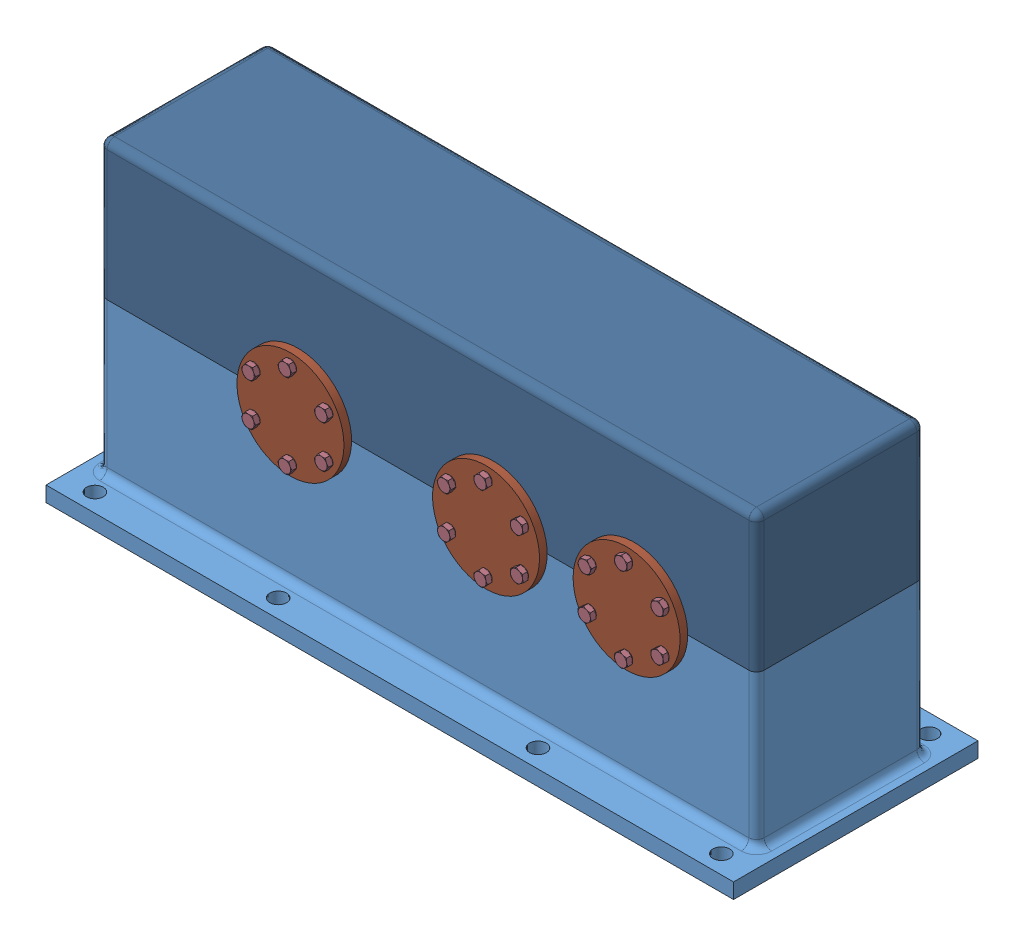
SolidWorks assembly gear box 1, configuration Default. Lengths in mm.
Overall size (450 208.96 200).
57 component instances, 13 part files, 131 mates.
Components (placement in the parent):
- housing-1: housing [Default] at (201.3675 171.3097 333.5833) size (450 110 160)
- 23T GEAR-1: 23T GEAR [Default] at (343.8267 281.2328 311.9535) x (0 0 -1) z (-0.038313 0.999266 0) size (25 49.84 49.95)
- 69T GEAR-1: 69T GEAR [Default] at (242.5131 286.1435 311.7084) x (0 0 -1) z (0.81521 -0.579166 0) size (25 141.95 141.99)
- 34T 2.5M GEAR-1: 34T 2.5M GEAR [Default] at (241.1812 276.7312 345.5837) x (0 0 -1) z (0.81521 -0.579166 0) size (25 89.74 90)
- 69T 2.5M GEAR-1: 69T 2.5M GEAR [Default] at (102.958 286.2942 359.4922) x (0 0 -1) z (-1 -0.00092 0) size (25 177.44 177.48)
- input shaft-1: input shaft [Default] at (336.3675 281.3097 388.5833) x (0 0 -1) z (-0.038313 0.999266 0) size (175 25 28.29)
- 1st stage shaft-1: 1st stage shaft [Default] at (244.3675 281.3097 388.5833) x (0 0 -1) z (0.81521 -0.579166 0) size (110 25 25)
- output shaft-1: output shaft [Default] at (116.3675 281.3097 388.5833) x (0 0 -1) z (-1 -0.00092 0) size (165 25 25)
- 6004 bearing-1: 6004 bearing [Default] at (123.168 277.2526 295.2471) x (0 0 -1) z (1 0 0) size (12 42 42)
- 6004 bearing-2: 6004 bearing [Default] at (251.168 277.2526 295.2471) x (0 0 -1) z (1 0 0) size (12 42 42)
- 6004 bearing-3: 6004 bearing [Default] at (343.2349 285.2524 387.2471) x (0 0 -1) z (0.489674 0.871906 0) size (12 42 42)
- 6004 bearing-4: 6004 bearing [Default] at (343.1288 277.1876 295.2471) x (0 0 -1) z (0.999954 -0.009577 0) size (12 42 42)
- 6004 bearing-5: 6004 bearing [Default] at (251.168 277.2526 387.2471) x (0 0 -1) z (1 0 0) size (12 42 42)
- 6004 bearing-6: 6004 bearing [Default] at (123.6132 278.115 387.2471) x (0 0 -1) z (0.99249 0.122329 0) size (12 42 42)
- top housing-1: top housing [Default] at (201.3675 281.3097 333.5833) size (430 90 110)
- bearing cover 01-1: bearing cover 01 [Default] at (116.3675 281.3097 393.5833) x (0 0 -1) z (0.866025 0.5 0) size (8 70 70)
- bearing cover 01-2: bearing cover 01 [Default] at (244.3675 281.3097 393.5833) x (0 0 -1) z (0.866025 0.5 0) size (8 70 70)
- bearing cover 01-3: bearing cover 01 [Default] at (336.3675 281.3097 393.5833) x (0 0 -1) z (-0.866025 0.5 0) size (8 70 70)
- bearing cover 01-5: bearing cover 01 [Default] at (244.3675 281.3097 273.5833) x (0 0 1) z (-0.866025 0.5 0) size (8 70 70)
- bearing cover 02-3: bearing cover 02 [Default] at (336.3675 281.3097 273.5833) x (0 0 1) z (-0.866025 -0.5 0) size (8 70 70)
- bearing cover 02-4: bearing cover 02 [Default] at (116.3675 281.3097 273.5833) x (0 0 1) z (-0.866025 0.5 0) size (8 70 70)
- hex bolt gradec_iso-2: hex bolt gradec_iso [ISO 4016 - M5 x 25 x 16-WN] at (336.3675 308.8097 397.4583) x (0 0 -1) z (0.550968 0.834527 0) size (28.88 9.24 8)
- hex bolt gradec_iso-3: hex bolt gradec_iso [ISO 4016 - M5 x 25 x 16-WN] at (360.1832 295.0597 397.4583) x (0 0 -1) z (-0.354568 0.93503 0) size (28.88 9.24 8)
- hex bolt gradec_iso-4: hex bolt gradec_iso [ISO 4016 - M5 x 25 x 16-WN] at (360.1832 267.5597 397.4583) x (0 0 -1) z (0.631634 -0.775267 0) size (28.88 9.24 8)
- hex bolt gradec_iso-5: hex bolt gradec_iso [ISO 4016 - M5 x 25 x 16-WN] at (336.3675 253.8097 397.4583) x (0 0 -1) z (0.631634 -0.775267 0) size (28.88 9.24 8)
- hex bolt gradec_iso-6: hex bolt gradec_iso [ISO 4016 - M5 x 25 x 16-WN] at (312.5518 267.5597 397.4583) x (0 0 -1) z (0.631634 -0.775267 0) size (28.88 9.24 8)
- hex bolt gradec_iso-7: hex bolt gradec_iso [ISO 4016 - M5 x 25 x 16-WN] at (312.5518 295.0597 397.4583) x (0 0 -1) z (0.762541 0.64694 0) size (28.88 9.24 8)
- hex bolt gradec_iso-8: hex bolt gradec_iso [ISO 4016 - M5 x 25 x 16-WN] at (268.1832 295.0597 397.4583) x (0 0 -1) z (0.631634 -0.775267 0) size (28.88 9.24 8)
- hex bolt gradec_iso-9: hex bolt gradec_iso [ISO 4016 - M5 x 25 x 16-WN] at (268.1832 267.5597 397.4583) x (0 0 -1) z (0.99571 0.092525 0) size (28.88 9.24 8)
- hex bolt gradec_iso-10: hex bolt gradec_iso [ISO 4016 - M5 x 25 x 16-WN] at (244.3675 308.8097 397.4583) x (0 0 -1) z (0.242994 0.970028 0) size (28.88 9.24 8)
- hex bolt gradec_iso-11: hex bolt gradec_iso [ISO 4016 - M5 x 25 x 16-WN] at (220.5518 295.0597 397.4583) x (0 0 -1) z (-0.834184 0.551486 0) size (28.88 9.24 8)
- hex bolt gradec_iso-12: hex bolt gradec_iso [ISO 4016 - M5 x 25 x 16-WN] at (244.3675 253.8097 397.4583) x (0 0 -1) z (0.242994 0.970028 0) size (28.88 9.24 8)
- hex bolt gradec_iso-13: hex bolt gradec_iso [ISO 4016 - M5 x 25 x 16-WN] at (220.5518 267.5597 397.4583) x (0 0 -1) z (0.242994 0.970028 0) size (28.88 9.24 8)
- hex bolt gradec_iso-14: hex bolt gradec_iso [ISO 4016 - M5 x 25 x 16-WN] at (140.1832 295.0597 397.4583) x (0 0 -1) z (-0.834184 0.551486 0) size (28.88 9.24 8)
- hex bolt gradec_iso-15: hex bolt gradec_iso [ISO 4016 - M5 x 25 x 16-WN] at (116.3675 308.8097 397.4583) x (0 0 -1) z (-0.834184 0.551486 0) size (28.88 9.24 8)
- hex bolt gradec_iso-16: hex bolt gradec_iso [ISO 4016 - M5 x 25 x 16-WN] at (92.5518 295.0597 397.4583) x (0 0 -1) z (-0.834184 0.551486 0) size (28.88 9.24 8)
- hex bolt gradec_iso-17: hex bolt gradec_iso [ISO 4016 - M5 x 25 x 16-WN] at (92.5518 267.5597 397.4583) x (0 0 -1) z (-0.834184 0.551486 0) size (28.88 9.24 8)
- hex bolt gradec_iso-18: hex bolt gradec_iso [ISO 4016 - M5 x 25 x 16-WN] at (116.3675 253.8097 397.4583) x (0 0 -1) z (-0.834184 0.551486 0) size (28.88 9.24 8)
- hex bolt gradec_iso-19: hex bolt gradec_iso [ISO 4016 - M5 x 25 x 16-WN] at (140.1832 267.5597 397.4583) x (0 0 -1) z (-0.834184 0.551486 0) size (28.88 9.24 8)
- hex bolt gradec_iso-20: hex bolt gradec_iso [ISO 4016 - M5 x 25 x 16-WN] at (336.3675 308.8097 269.7083) x (0 0 1) z (0.291733 0.9565 0) size (28.88 9.24 8)
- hex bolt gradec_iso-21: hex bolt gradec_iso [ISO 4016 - M5 x 25 x 16-WN] at (360.1832 295.0597 269.7083) x (0 0 1) z (0.291733 0.9565 0) size (28.88 9.24 8)
- hex bolt gradec_iso-23: hex bolt gradec_iso [ISO 4016 - M5 x 25 x 16-WN] at (360.1832 267.5597 269.7083) x (0 0 1) z (0.291733 0.9565 0) size (28.88 9.24 8)
- hex bolt gradec_iso-24: hex bolt gradec_iso [ISO 4016 - M5 x 25 x 16-WN] at (336.3675 253.8097 269.7083) x (0 0 1) z (0.291733 0.9565 0) size (28.88 9.24 8)
- hex bolt gradec_iso-25: hex bolt gradec_iso [ISO 4016 - M5 x 25 x 16-WN] at (312.5518 295.0597 269.7083) x (0 0 1) z (0.291733 0.9565 0) size (28.88 9.24 8)
- hex bolt gradec_iso-26: hex bolt gradec_iso [ISO 4016 - M5 x 25 x 16-WN] at (312.5518 267.5597 269.7083) x (0 0 1) z (0.291733 0.9565 0) size (28.88 9.24 8)
- hex bolt gradec_iso-27: hex bolt gradec_iso [ISO 4016 - M5 x 25 x 16-WN] at (268.1832 295.0597 269.7083) x (0 0 1) z (0.291733 0.9565 0) size (28.88 9.24 8)
- hex bolt gradec_iso-28: hex bolt gradec_iso [ISO 4016 - M5 x 25 x 16-WN] at (244.3675 308.8097 269.7083) x (0 0 1) z (0.291733 0.9565 0) size (28.88 9.24 8)
- hex bolt gradec_iso-30: hex bolt gradec_iso [ISO 4016 - M5 x 25 x 16-WN] at (220.5518 295.0597 269.7083) x (0 0 1) z (0.291733 0.9565 0) size (28.88 9.24 8)
- hex bolt gradec_iso-31: hex bolt gradec_iso [ISO 4016 - M5 x 25 x 16-WN] at (220.5518 267.5597 269.7083) x (0 0 1) z (0.291733 0.9565 0) size (28.88 9.24 8)
- hex bolt gradec_iso-32: hex bolt gradec_iso [ISO 4016 - M5 x 25 x 16-WN] at (244.3675 253.8097 269.7083) x (0 0 1) z (0.291733 0.9565 0) size (28.88 9.24 8)
- hex bolt gradec_iso-33: hex bolt gradec_iso [ISO 4016 - M5 x 25 x 16-WN] at (268.1832 267.5597 269.7083) x (0 0 1) z (0.291733 0.9565 0) size (28.88 9.24 8)
- hex bolt gradec_iso-34: hex bolt gradec_iso [ISO 4016 - M5 x 25 x 16-WN] at (140.1832 295.0597 269.7083) x (0 0 1) z (0.291733 0.9565 0) size (28.88 9.24 8)
- hex bolt gradec_iso-35: hex bolt gradec_iso [ISO 4016 - M5 x 25 x 16-WN] at (116.3675 308.8097 269.7083) x (0 0 1) z (0.291733 0.9565 0) size (28.88 9.24 8)
- hex bolt gradec_iso-36: hex bolt gradec_iso [ISO 4016 - M5 x 25 x 16-WN] at (92.5518 295.0597 269.7083) x (0 0 1) z (0.291733 0.9565 0) size (28.88 9.24 8)
- hex bolt gradec_iso-37: hex bolt gradec_iso [ISO 4016 - M5 x 25 x 16-WN] at (140.1832 267.5597 269.7083) x (0 0 1) z (0.291733 0.9565 0) size (28.88 9.24 8)
- hex bolt gradec_iso-38: hex bolt gradec_iso [ISO 4016 - M5 x 25 x 16-WN] at (116.3675 253.8097 269.7083) x (0 0 1) z (0.291733 0.9565 0) size (28.88 9.24 8)
- hex bolt gradec_iso-39: hex bolt gradec_iso [ISO 4016 - M5 x 25 x 16-WN] at (92.5518 267.5597 269.7083) x (0 0 1) z (0.291733 0.9565 0) size (28.88 9.24 8)
Mates (geometry in assembly coordinates):
- Concentric1: concentric aligned: cylinder of housing-1 through (244.3675 281.3097 253.5833) axis (0 0 1) radius 21; cylinder of 69T GEAR-1 through (244.3675 281.3097 278.5833) axis (0 0 1) radius 10
- Concentric2: concentric aligned: cylinder of housing-1 through (336.3675 281.3097 253.5833) axis (0 0 1) radius 21; cylinder of 23T GEAR-1 through (336.3675 281.3097 278.5833) axis (0 0 1) radius 10
- Coincident1: coincident aligned: plane of 23T GEAR-1 through (336.3675 281.3097 328.5833) normal (0 0 1); plane of 69T GEAR-1 through (244.3675 281.3097 328.5833) normal (0 0 1)
- Coincident2: coincident aligned: plane of 23T GEAR-1 through (336.3675 281.3097 328.5833) normal (0 0 1); plane of 69T GEAR-1 through (244.3675 281.3097 328.5833) normal (0 0 1)
- Concentric3: concentric aligned: cylinder of housing-1 through (116.3675 281.3097 253.5833) axis (0 0 1) radius 21; cylinder of 69T 2.5M GEAR-1 through (116.3675 281.3097 313.5833) axis (0 0 1) radius 10
- Concentric4: concentric aligned: cylinder of housing-1 through (244.3675 281.3097 253.5833) axis (0 0 1) radius 21; cylinder of 34T 2.5M GEAR-1 through (244.3675 281.3097 313.5833) axis (0 0 1) radius 10
- Coincident3: coincident aligned: plane of 34T 2.5M GEAR-1 through (244.3675 281.3097 363.5833) normal (0 0 1); plane of 69T 2.5M GEAR-1 through (116.3675 281.3097 363.5833) normal (0 0 1)
- Concentric5: concentric anti-aligned: cylinder of 23T GEAR-1 through (336.3675 281.3097 278.5833) axis (0 0 1) radius 10; cylinder of input shaft-1 through (336.3675 281.3097 213.5833) axis (0 0 -1) radius 10
- Coincident4: coincident anti-aligned: plane of 23T GEAR-1 through (336.3675 281.3097 328.5833) normal (0 0 1); plane of input shaft-1 through (336.8464 268.8189 328.5833) normal (0 0 -1)
- Coincident5: coincident aligned: plane of 23T GEAR-1 through (323.6919 277.8215 278.5833) normal (-0.038313 0.999266 0); plane of input shaft-1 through (329.4876 278.0437 325.5833) normal (-0.038313 0.999266 0)
- Coincident6: coincident aligned: plane of housing-1 through (-13.6325 281.3097 388.5833) normal (0 0 1); plane of input shaft-1 through (336.3675 281.3097 388.5833) normal (0 0 1)
- Coincident7: coincident anti-aligned: circle of 34T 2.5M GEAR-1; cylinder of 1st stage shaft-1 through (244.3675 281.3097 278.5833) axis (0 0 -1) radius 10
- Coincident8: coincident anti-aligned: plane of 34T 2.5M GEAR-1 through (244.3675 281.3097 338.5833) normal (0 0 -1); plane of 1st stage shaft-1 through (250.1592 289.4618 338.5833) normal (0 0 1)
- Coincident9: coincident aligned: plane of 34T 2.5M GEAR-1 through (249.3352 293.4819 313.5833) normal (0.81521 -0.579166 0); plane of 1st stage shaft-1 through (245.9761 288.7536 341.5833) normal (0.81521 -0.579166 0)
- Coincident10: coincident aligned: plane of 69T GEAR-1 through (249.3352 293.4819 278.5833) normal (0.81521 -0.579166 0); plane of 1st stage shaft-1 through (245.9761 288.7536 325.5833) normal (0.81521 -0.579166 0)
- Coincident11: coincident anti-aligned: plane of 69T GEAR-1 through (244.3675 281.3097 328.5833) normal (0 0 1); plane of 1st stage shaft-1 through (251.6071 291.4998 328.5833) normal (0 0 -1)
- Concentric6: concentric anti-aligned: cylinder of 69T 2.5M GEAR-1 through (116.3675 281.3097 313.5833) axis (0 0 1) radius 10; cylinder of output shaft-1 through (116.3675 281.3097 223.5833) axis (0 0 -1) radius 10
- Coincident12: coincident aligned: plane of 69T 2.5M GEAR-1 through (119.3793 268.5124 313.5833) normal (-1 -0.00092 0); plane of output shaft-1 through (119.374 274.3124 360.5833) normal (-1 -0.00092 0)
- Coincident13: coincident anti-aligned: plane of 69T 2.5M GEAR-1 through (116.3675 281.3097 363.5833) normal (0 0 1); plane of output shaft-1 through (116.379 268.8097 363.5833) normal (0 0 -1)
- Concentric7: concentric anti-aligned: cylinder of housing-1 through (336.3675 281.3097 253.5833) axis (0 0 1) radius 21; cylinder of 6004 bearing-3 through (336.3675 281.3097 400.2208) axis (0 0 -1) radius 21
- Concentric8: concentric aligned: cylinder of 1st stage shaft-1 through (244.3675 281.3097 278.5833) axis (0 0 -1) radius 10; cylinder of 6004 bearing-5 through (244.3675 281.3097 400.2208) axis (0 0 -1) radius 21
- Concentric10: concentric anti-aligned: cylinder of housing-1 through (116.3675 281.3097 253.5833) axis (0 0 1) radius 21; cylinder of 6004 bearing-6 through (116.3675 281.3097 400.2208) axis (0 0 -1) radius 21
- Concentric11: concentric anti-aligned: cylinder of housing-1 through (336.3675 281.3097 253.5833) axis (0 0 1) radius 21; cylinder of 6004 bearing-4 through (336.3675 281.3097 308.2208) axis (0 0 -1) radius 21
- Concentric12: concentric anti-aligned: cylinder of housing-1 through (244.3675 281.3097 253.5833) axis (0 0 1) radius 21; cylinder of 6004 bearing-2 through (244.3675 281.3097 308.2208) axis (0 0 -1) radius 21
- Concentric13: concentric anti-aligned: cylinder of housing-1 through (116.3675 281.3097 253.5833) axis (0 0 1) radius 21; cylinder of 6004 bearing-1 through (116.3675 281.3097 308.2208) axis (0 0 -1) radius 21
- Coincident14: coincident anti-aligned: plane of output shaft-1 through (116.3767 271.3097 373.5833) normal (0 0 1); plane of 6004 bearing-6 through (115.0708 291.8301 373.5833) normal (0 0 -1)
- Coincident15: coincident aligned: plane of housing-1 through (1.3675 281.3097 373.5833) normal (0 0 -1); plane of 6004 bearing-5 through (244.3675 291.9097 373.5833) normal (0 0 -1)
- Coincident16: coincident aligned: plane of housing-1 through (1.3675 281.3097 373.5833) normal (0 0 -1); plane of 6004 bearing-3 through (327.1253 286.5002 373.5833) normal (0 0 -1)
- Coincident17: coincident aligned: plane of housing-1 through (1.3675 281.3097 293.5833) normal (0 0 1); plane of 6004 bearing-4 through (336.4949 294.6091 293.5833) normal (0 0 1)
- Coincident18: coincident aligned: plane of housing-1 through (1.3675 281.3097 293.5833) normal (0 0 1); plane of 6004 bearing-2 through (244.3675 294.6097 293.5833) normal (0 0 1)
- Coincident19: coincident aligned: plane of housing-1 through (1.3675 281.3097 293.5833) normal (0 0 1); plane of 6004 bearing-1 through (116.3675 294.6097 293.5833) normal (0 0 1)
- GearMate4: gear = 69 : 23 mm: cylinder of 23T GEAR-1 through (336.3675 281.3097 338.5833) axis (0 0 1) radius 25; cylinder of 69T GEAR-1 through (244.3675 281.3097 338.5833) axis (0 0 1) radius 71
- GearMate5: gear = 69 : 34 mm: cylinder of 34T 2.5M GEAR-1 through (244.3675 281.3097 338.5833) axis (0 0 1) radius 39.374; cylinder of 69T 2.5M GEAR-1 through (116.3675 281.3097 338.5833) axis (0 0 1) radius 83.124
- Coincident21: coincident anti-aligned: plane of output shaft-1 through (116.3767 271.3097 373.5833) normal (0 0 1); plane of 6004 bearing-6 through (115.0708 291.8301 373.5833) normal (0 0 -1)
- Coincident22: coincident anti-aligned: plane of 69T 2.5M GEAR-1 through (116.3675 281.3097 363.5833) normal (0 0 1); circle of output shaft-1
- Coincident23: coincident aligned: plane of housing-1 through (-13.6325 281.3097 388.5833) normal (0 0 1); plane of top housing-1 through (-13.6325 361.3097 388.5833) normal (0 0 1)
- Coincident24: coincident aligned: plane of housing-1 through (-13.6325 281.3097 388.5833) normal (-1 0 0); plane of top housing-1 through (-13.6325 361.3097 388.5833) normal (-1 0 0)
- Coincident25: coincident anti-aligned: plane of housing-1 through (201.3675 281.3097 333.5833) normal (0 1 0); plane of top housing-1 through (201.3675 281.3097 333.5833) normal (0 -1 0)
- Concentric18: concentric anti-aligned: cylinder of top housing-1 through (116.3675 281.3097 192.5833) axis (0 0 1) radius 21; cylinder of bearing cover 01-1 through (116.3675 281.3097 388.5833) axis (0 0 -1) radius 35
- Concentric19: concentric anti-aligned: cylinder of housing-1 through (244.3675 281.3097 253.5833) axis (0 0 1) radius 21; cylinder of bearing cover 01-2 through (244.3675 281.3097 388.5833) axis (0 0 -1) radius 35
- Concentric20: concentric anti-aligned: cylinder of housing-1 through (336.3675 281.3097 253.5833) axis (0 0 1) radius 21; cylinder of bearing cover 01-3 through (336.3675 281.3097 388.5833) axis (0 0 -1) radius 35
- Concentric21: concentric aligned: cylinder of housing-1 through (336.3675 281.3097 253.5833) axis (0 0 1) radius 21; cylinder of bearing cover 02-3 through (336.3675 281.3097 278.5833) axis (0 0 1) radius 35
- Concentric22: concentric aligned: cylinder of housing-1 through (116.3675 281.3097 253.5833) axis (0 0 1) radius 21; cylinder of bearing cover 02-4 through (116.3675 281.3097 278.5833) axis (0 0 1) radius 35
- Concentric23: concentric aligned: cylinder of housing-1 through (244.3675 281.3097 253.5833) axis (0 0 1) radius 21; cylinder of bearing cover 01-5 through (244.3675 281.3097 278.5833) axis (0 0 1) radius 35
- Parallel5: parallel anti-aligned: cylinder of top housing-1 through (336.3675 308.8097 388.5833) axis (0 0 1) radius 2.1; cylinder of bearing cover 01-3 through (312.5518 267.5597 398.5833) axis (0 0 -1) radius 3
- Parallel6: parallel anti-aligned: cylinder of top housing-1 through (336.3675 308.8097 388.5833) axis (0 0 1) radius 2.1; cylinder of bearing cover 01-3 through (336.3675 253.8097 398.5833) axis (0 0 -1) radius 3
- Parallel7: parallel anti-aligned: cylinder of top housing-1 through (220.5518 295.0597 388.5833) axis (0 0 1) radius 2.1; cylinder of bearing cover 01-2 through (220.5518 295.0597 398.5833) axis (0 0 -1) radius 3
- Concentric27: concentric anti-aligned: cylinder of housing-1 through (116.3675 253.8097 388.5833) axis (0 0 1) radius 2.1; cylinder of bearing cover 01-1 through (116.3675 253.8097 398.5833) axis (0 0 -1) radius 3
- Concentric28: concentric anti-aligned: cylinder of housing-1 through (336.3675 253.8097 278.5833) axis (0 0 -1) radius 2.1; cylinder of bearing cover 02-3 through (336.3675 253.8097 268.5833) axis (0 0 1) radius 3
- Concentric29: concentric anti-aligned: cylinder of housing-1 through (220.5518 267.5597 278.5833) axis (0 0 -1) radius 2.1; cylinder of bearing cover 01-5 through (220.5518 267.5597 268.5833) axis (0 0 1) radius 3
- Concentric30: concentric anti-aligned: cylinder of housing-1 through (92.5518 267.5597 278.5833) axis (0 0 -1) radius 2.1; cylinder of bearing cover 02-4 through (92.5518 267.5597 268.5833) axis (0 0 1) radius 3
- Coincident26: coincident anti-aligned: plane of top housing-1 through (-13.6325 361.3097 388.5833) normal (0 0 1); plane of bearing cover 01-3 through (318.8675 250.9988 388.5833) normal (0 0 -1)
- Coincident27: coincident anti-aligned: plane of top housing-1 through (-13.6325 361.3097 388.5833) normal (0 0 1); plane of bearing cover 01-2 through (226.8675 311.6206 388.5833) normal (0 0 -1)
- Coincident28: coincident anti-aligned: plane of top housing-1 through (-13.6325 361.3097 388.5833) normal (0 0 1); plane of bearing cover 01-1 through (98.8675 311.6206 388.5833) normal (0 0 -1)
- Coincident29: coincident anti-aligned: plane of top housing-1 through (-13.6325 361.3097 278.5833) normal (0 0 -1); plane of bearing cover 02-3 through (318.8675 311.6206 278.5833) normal (0 0 1)
- Coincident30: coincident anti-aligned: plane of top housing-1 through (-13.6325 361.3097 278.5833) normal (0 0 -1); plane of bearing cover 01-5 through (261.8675 311.6206 278.5833) normal (0 0 1)
- Coincident31: coincident anti-aligned: plane of top housing-1 through (-13.6325 361.3097 278.5833) normal (0 0 -1); plane of bearing cover 02-4 through (133.8675 311.6206 278.5833) normal (0 0 1)
- Concentric32: concentric anti-aligned: circle of bearing cover 01-3; circle of hex bolt gradec_iso-2
- Coincident32: coincident anti-aligned: plane of bearing cover 01-3 through (336.3675 281.3097 393.5833) normal (0 0 1); plane of hex bolt gradec_iso-2 through (332.513 311.3545 393.5833) normal (0 0 -1)
- Concentric331: concentric anti-aligned: cylinder of bearing cover 01-3 through (360.1832 295.0597 398.5833) axis (0 0 -1) radius 3; cylinder of hex bolt gradec_iso-3 through (360.1832 295.0597 397.4583) axis (0 0 1) radius 2.5
- Coincident331: coincident anti-aligned: plane of bearing cover 01-3 through (336.3675 281.3097 393.5833) normal (0 0 1); plane of hex bolt gradec_iso-3 through (355.8645 293.422 393.5833) normal (0 0 -1)
- Concentric34: concentric anti-aligned: circle of housing-1; cylinder of bearing cover 01-3 through (360.1832 267.5597 398.5833) axis (0 0 -1) radius 3
- Concentric351: concentric anti-aligned: cylinder of bearing cover 01-3 through (360.1832 267.5597 398.5833) axis (0 0 -1) radius 3; cylinder of hex bolt gradec_iso-4 through (360.1832 267.5597 397.4583) axis (0 0 1) radius 2.5
- Coincident341: coincident anti-aligned: plane of bearing cover 01-3 through (336.3675 281.3097 393.5833) normal (0 0 1); plane of hex bolt gradec_iso-4 through (363.764 270.4771 393.5833) normal (0 0 -1)
- Concentric361: concentric anti-aligned: cylinder of bearing cover 01-3 through (336.3675 253.8097 398.5833) axis (0 0 -1) radius 3; cylinder of hex bolt gradec_iso-5 through (336.3675 253.8097 397.4583) axis (0 0 1) radius 2.5
- Coincident351: coincident anti-aligned: plane of bearing cover 01-3 through (336.3675 281.3097 393.5833) normal (0 0 1); plane of hex bolt gradec_iso-5 through (339.9483 256.7271 393.5833) normal (0 0 -1)
- Concentric371: concentric anti-aligned: cylinder of bearing cover 01-3 through (312.5518 267.5597 398.5833) axis (0 0 -1) radius 3; cylinder of hex bolt gradec_iso-6 through (312.5518 267.5597 397.4583) axis (0 0 1) radius 2.5
- Coincident361: coincident anti-aligned: plane of bearing cover 01-3 through (336.3675 281.3097 393.5833) normal (0 0 1); plane of hex bolt gradec_iso-6 through (316.1326 270.4771 393.5833) normal (0 0 -1)
- Concentric381: concentric anti-aligned: cylinder of bearing cover 01-3 through (312.5518 295.0597 398.5833) axis (0 0 -1) radius 3; cylinder of hex bolt gradec_iso-7 through (312.5518 295.0597 397.4583) axis (0 0 1) radius 2.5
- Coincident371: coincident anti-aligned: plane of bearing cover 01-3 through (336.3675 281.3097 393.5833) normal (0 0 1); plane of hex bolt gradec_iso-7 through (309.5638 298.5817 393.5833) normal (0 0 -1)
- Concentric391: concentric anti-aligned: cylinder of bearing cover 01-2 through (268.1832 295.0597 398.5833) axis (0 0 -1) radius 3; cylinder of hex bolt gradec_iso-8 through (268.1832 295.0597 397.4583) axis (0 0 1) radius 2.5
- Coincident381: coincident anti-aligned: plane of bearing cover 01-2 through (244.3675 281.3097 393.5833) normal (0 0 1); plane of hex bolt gradec_iso-8 through (271.764 297.9771 393.5833) normal (0 0 -1)
- Concentric401: concentric anti-aligned: cylinder of bearing cover 01-2 through (268.1832 267.5597 398.5833) axis (0 0 -1) radius 3; cylinder of hex bolt gradec_iso-9 through (268.1832 267.5597 397.4583) axis (0 0 1) radius 2.5
- Coincident391: coincident anti-aligned: plane of bearing cover 01-2 through (244.3675 281.3097 393.5833) normal (0 0 1); plane of hex bolt gradec_iso-9 through (267.7559 272.1587 393.5833) normal (0 0 -1)
- Concentric411: concentric anti-aligned: cylinder of bearing cover 01-2 through (244.3675 308.8097 398.5833) axis (0 0 -1) radius 3; cylinder of hex bolt gradec_iso-10 through (244.3675 308.8097 397.4583) axis (0 0 1) radius 2.5
- Coincident401: coincident anti-aligned: plane of bearing cover 01-2 through (244.3675 281.3097 393.5833) normal (0 0 1); plane of hex bolt gradec_iso-10 through (239.8872 309.932 393.5833) normal (0 0 -1)
- Concentric421: concentric anti-aligned: cylinder of bearing cover 01-2 through (220.5518 295.0597 398.5833) axis (0 0 -1) radius 3; cylinder of hex bolt gradec_iso-11 through (220.5518 295.0597 397.4583) axis (0 0 1) radius 2.5
- Coincident411: coincident anti-aligned: plane of bearing cover 01-2 through (244.3675 281.3097 393.5833) normal (0 0 1); plane of hex bolt gradec_iso-11 through (218.0046 291.2068 393.5833) normal (0 0 -1)
- Concentric43: concentric aligned: circle of housing-1; circle of bearing cover 01-2
- Concentric441: concentric anti-aligned: cylinder of bearing cover 01-2 through (244.3675 253.8097 398.5833) axis (0 0 -1) radius 3; cylinder of hex bolt gradec_iso-12 through (244.3675 253.8097 397.4583) axis (0 0 1) radius 2.5
- Coincident421: coincident anti-aligned: plane of bearing cover 01-2 through (244.3675 281.3097 393.5833) normal (0 0 1); plane of hex bolt gradec_iso-12 through (239.8872 254.932 393.5833) normal (0 0 -1)
- Concentric451: concentric anti-aligned: cylinder of bearing cover 01-2 through (220.5518 267.5597 398.5833) axis (0 0 -1) radius 3; cylinder of hex bolt gradec_iso-13 through (220.5518 267.5597 397.4583) axis (0 0 1) radius 2.5
- Coincident431: coincident anti-aligned: plane of bearing cover 01-2 through (244.3675 281.3097 393.5833) normal (0 0 1); plane of hex bolt gradec_iso-13 through (216.0715 268.682 393.5833) normal (0 0 -1)
- Concentric461: concentric anti-aligned: cylinder of bearing cover 01-1 through (140.1832 295.0597 398.5833) axis (0 0 -1) radius 3; cylinder of hex bolt gradec_iso-14 through (140.1832 295.0597 397.4583) axis (0 0 1) radius 2.5
- Coincident441: coincident anti-aligned: plane of bearing cover 01-1 through (116.3675 281.3097 393.5833) normal (0 0 1); plane of hex bolt gradec_iso-14 through (137.636 291.2068 393.5833) normal (0 0 -1)
- Concentric471: concentric anti-aligned: cylinder of bearing cover 01-1 through (116.3675 308.8097 398.5833) axis (0 0 -1) radius 3; cylinder of hex bolt gradec_iso-15 through (116.3675 308.8097 397.4583) axis (0 0 1) radius 2.5
- Coincident451: coincident anti-aligned: plane of bearing cover 01-1 through (116.3675 281.3097 393.5833) normal (0 0 1); plane of hex bolt gradec_iso-15 through (113.8203 304.9568 393.5833) normal (0 0 -1)
- Concentric481: concentric anti-aligned: cylinder of bearing cover 01-1 through (92.5518 295.0597 398.5833) axis (0 0 -1) radius 3; cylinder of hex bolt gradec_iso-16 through (92.5518 295.0597 397.4583) axis (0 0 1) radius 2.5
- Coincident461: coincident anti-aligned: plane of bearing cover 01-1 through (116.3675 281.3097 393.5833) normal (0 0 1); plane of hex bolt gradec_iso-16 through (90.0046 291.2068 393.5833) normal (0 0 -1)
- Concentric491: concentric anti-aligned: cylinder of bearing cover 01-1 through (92.5518 267.5597 398.5833) axis (0 0 -1) radius 3; cylinder of hex bolt gradec_iso-17 through (92.5518 267.5597 397.4583) axis (0 0 1) radius 2.5
- Coincident471: coincident anti-aligned: plane of bearing cover 01-1 through (116.3675 281.3097 393.5833) normal (0 0 1); plane of hex bolt gradec_iso-17 through (90.0046 263.7068 393.5833) normal (0 0 -1)
- Concentric501: concentric anti-aligned: cylinder of bearing cover 01-1 through (116.3675 253.8097 398.5833) axis (0 0 -1) radius 3; cylinder of hex bolt gradec_iso-18 through (116.3675 253.8097 397.4583) axis (0 0 1) radius 2.5
- Coincident481: coincident anti-aligned: plane of bearing cover 01-1 through (116.3675 281.3097 393.5833) normal (0 0 1); plane of hex bolt gradec_iso-18 through (113.8203 249.9568 393.5833) normal (0 0 -1)
- Concentric511: concentric anti-aligned: cylinder of bearing cover 01-1 through (140.1832 267.5597 398.5833) axis (0 0 -1) radius 3; cylinder of hex bolt gradec_iso-19 through (140.1832 267.5597 397.4583) axis (0 0 1) radius 2.5
- Coincident491: coincident anti-aligned: plane of bearing cover 01-1 through (116.3675 281.3097 393.5833) normal (0 0 1); plane of hex bolt gradec_iso-19 through (137.636 263.7068 393.5833) normal (0 0 -1)
- Coincident51: coincident anti-aligned: plane of bearing cover 02-3 through (336.3675 281.3097 273.5833) normal (0 0 -1); plane of hex bolt gradec_iso-20 through (340.7854 307.4622 273.5833) normal (0 0 1)
- Concentric54: concentric anti-aligned: cylinder of bearing cover 02-3 through (336.3675 308.8097 268.5833) axis (0 0 1) radius 3; cylinder of hex bolt gradec_iso-20 through (336.3675 308.8097 269.7083) axis (0 0 -1) radius 2.5
- Concentric551: concentric anti-aligned: cylinder of bearing cover 02-3 through (360.1832 295.0597 268.5833) axis (0 0 1) radius 3; cylinder of hex bolt gradec_iso-21 through (360.1832 295.0597 269.7083) axis (0 0 -1) radius 2.5
- Coincident521: coincident anti-aligned: plane of bearing cover 02-3 through (336.3675 281.3097 273.5833) normal (0 0 -1); plane of hex bolt gradec_iso-21 through (364.6011 293.7122 273.5833) normal (0 0 1)
- Concentric571: concentric anti-aligned: cylinder of bearing cover 02-3 through (360.1832 267.5597 268.5833) axis (0 0 1) radius 3; cylinder of hex bolt gradec_iso-23 through (360.1832 267.5597 269.7083) axis (0 0 -1) radius 2.5
- Coincident541: coincident anti-aligned: plane of bearing cover 02-3 through (336.3675 281.3097 273.5833) normal (0 0 -1); plane of hex bolt gradec_iso-23 through (364.6011 266.2122 273.5833) normal (0 0 1)
- Concentric581: concentric anti-aligned: cylinder of bearing cover 02-3 through (336.3675 253.8097 268.5833) axis (0 0 1) radius 3; cylinder of hex bolt gradec_iso-24 through (336.3675 253.8097 269.7083) axis (0 0 -1) radius 2.5
- Coincident551: coincident anti-aligned: plane of bearing cover 02-3 through (336.3675 281.3097 273.5833) normal (0 0 -1); plane of hex bolt gradec_iso-24 through (340.7854 252.4622 273.5833) normal (0 0 1)
- Concentric591: concentric anti-aligned: cylinder of bearing cover 02-3 through (312.5518 295.0597 268.5833) axis (0 0 1) radius 3; cylinder of hex bolt gradec_iso-25 through (312.5518 295.0597 269.7083) axis (0 0 -1) radius 2.5
- Coincident561: coincident anti-aligned: plane of bearing cover 02-3 through (336.3675 281.3097 273.5833) normal (0 0 -1); plane of hex bolt gradec_iso-25 through (316.9697 293.7122 273.5833) normal (0 0 1)
- Concentric601: concentric anti-aligned: cylinder of bearing cover 02-3 through (312.5518 267.5597 268.5833) axis (0 0 1) radius 3; cylinder of hex bolt gradec_iso-26 through (312.5518 267.5597 269.7083) axis (0 0 -1) radius 2.5
- Coincident571: coincident anti-aligned: plane of bearing cover 02-3 through (336.3675 281.3097 273.5833) normal (0 0 -1); plane of hex bolt gradec_iso-26 through (316.9697 266.2122 273.5833) normal (0 0 1)
- Concentric611: concentric anti-aligned: cylinder of bearing cover 01-5 through (268.1832 295.0597 268.5833) axis (0 0 1) radius 3; cylinder of hex bolt gradec_iso-27 through (268.1832 295.0597 269.7083) axis (0 0 -1) radius 2.5
- Coincident581: coincident anti-aligned: plane of bearing cover 01-5 through (244.3675 281.3097 273.5833) normal (0 0 -1); plane of hex bolt gradec_iso-27 through (272.6011 293.7122 273.5833) normal (0 0 1)
- Concentric621: concentric anti-aligned: cylinder of bearing cover 01-5 through (244.3675 308.8097 268.5833) axis (0 0 1) radius 3; cylinder of hex bolt gradec_iso-28 through (244.3675 308.8097 269.7083) axis (0 0 -1) radius 2.5
- Coincident591: coincident anti-aligned: plane of bearing cover 01-5 through (244.3675 281.3097 273.5833) normal (0 0 -1); plane of hex bolt gradec_iso-28 through (248.7854 307.4622 273.5833) normal (0 0 1)
- Concentric641: concentric anti-aligned: cylinder of bearing cover 01-5 through (220.5518 295.0597 268.5833) axis (0 0 1) radius 3; cylinder of hex bolt gradec_iso-30 through (220.5518 295.0597 269.7083) axis (0 0 -1) radius 2.5
- Coincident611: coincident anti-aligned: plane of bearing cover 01-5 through (244.3675 281.3097 273.5833) normal (0 0 -1); plane of hex bolt gradec_iso-30 through (224.9697 293.7122 273.5833) normal (0 0 1)
- Concentric651: concentric anti-aligned: cylinder of bearing cover 01-5 through (220.5518 267.5597 268.5833) axis (0 0 1) radius 3; cylinder of hex bolt gradec_iso-31 through (220.5518 267.5597 269.7083) axis (0 0 -1) radius 2.5
- Coincident621: coincident anti-aligned: plane of bearing cover 01-5 through (244.3675 281.3097 273.5833) normal (0 0 -1); plane of hex bolt gradec_iso-31 through (224.9697 266.2122 273.5833) normal (0 0 1)
- Concentric661: concentric anti-aligned: cylinder of bearing cover 01-5 through (244.3675 253.8097 268.5833) axis (0 0 1) radius 3; cylinder of hex bolt gradec_iso-32 through (244.3675 253.8097 269.7083) axis (0 0 -1) radius 2.5
- Coincident631: coincident anti-aligned: plane of bearing cover 01-5 through (244.3675 281.3097 273.5833) normal (0 0 -1); plane of hex bolt gradec_iso-32 through (248.7854 252.4622 273.5833) normal (0 0 1)
- Concentric671: concentric anti-aligned: cylinder of bearing cover 01-5 through (268.1832 267.5597 268.5833) axis (0 0 1) radius 3; cylinder of hex bolt gradec_iso-33 through (268.1832 267.5597 269.7083) axis (0 0 -1) radius 2.5
- Coincident641: coincident anti-aligned: plane of bearing cover 01-5 through (244.3675 281.3097 273.5833) normal (0 0 -1); plane of hex bolt gradec_iso-33 through (272.6011 266.2122 273.5833) normal (0 0 1)
- Concentric681: concentric anti-aligned: cylinder of bearing cover 02-4 through (140.1832 295.0597 268.5833) axis (0 0 1) radius 3; cylinder of hex bolt gradec_iso-34 through (140.1832 295.0597 269.7083) axis (0 0 -1) radius 2.5
- Coincident651: coincident anti-aligned: plane of bearing cover 02-4 through (116.3675 281.3097 273.5833) normal (0 0 -1); plane of hex bolt gradec_iso-34 through (144.6011 293.7122 273.5833) normal (0 0 1)
- Concentric691: concentric anti-aligned: cylinder of bearing cover 02-4 through (116.3675 308.8097 268.5833) axis (0 0 1) radius 3; cylinder of hex bolt gradec_iso-35 through (116.3675 308.8097 269.7083) axis (0 0 -1) radius 2.5
- Coincident661: coincident anti-aligned: plane of bearing cover 02-4 through (116.3675 281.3097 273.5833) normal (0 0 -1); plane of hex bolt gradec_iso-35 through (120.7854 307.4622 273.5833) normal (0 0 1)
- Concentric701: concentric anti-aligned: cylinder of bearing cover 02-4 through (92.5518 295.0597 268.5833) axis (0 0 1) radius 3; cylinder of hex bolt gradec_iso-36 through (92.5518 295.0597 269.7083) axis (0 0 -1) radius 2.5
- Coincident671: coincident anti-aligned: plane of bearing cover 02-4 through (116.3675 281.3097 273.5833) normal (0 0 -1); plane of hex bolt gradec_iso-36 through (96.9697 293.7122 273.5833) normal (0 0 1)
- Concentric711: concentric anti-aligned: cylinder of bearing cover 02-4 through (140.1832 267.5597 268.5833) axis (0 0 1) radius 3; cylinder of hex bolt gradec_iso-37 through (140.1832 267.5597 269.7083) axis (0 0 -1) radius 2.5
- Coincident681: coincident anti-aligned: plane of bearing cover 02-4 through (116.3675 281.3097 273.5833) normal (0 0 -1); plane of hex bolt gradec_iso-37 through (144.6011 266.2122 273.5833) normal (0 0 1)
- Concentric721: concentric anti-aligned: cylinder of bearing cover 02-4 through (116.3675 253.8097 268.5833) axis (0 0 1) radius 3; cylinder of hex bolt gradec_iso-38 through (116.3675 253.8097 269.7083) axis (0 0 -1) radius 2.5
- Coincident691: coincident anti-aligned: plane of bearing cover 02-4 through (116.3675 281.3097 273.5833) normal (0 0 -1); plane of hex bolt gradec_iso-38 through (120.7854 252.4622 273.5833) normal (0 0 1)
- Concentric731: concentric anti-aligned: cylinder of bearing cover 02-4 through (92.5518 267.5597 268.5833) axis (0 0 1) radius 3; cylinder of hex bolt gradec_iso-39 through (92.5518 267.5597 269.7083) axis (0 0 -1) radius 2.5
- Coincident701: coincident anti-aligned: plane of bearing cover 02-4 through (116.3675 281.3097 273.5833) normal (0 0 -1); plane of hex bolt gradec_iso-39 through (96.9697 266.2122 273.5833) normal (0 0 1)
